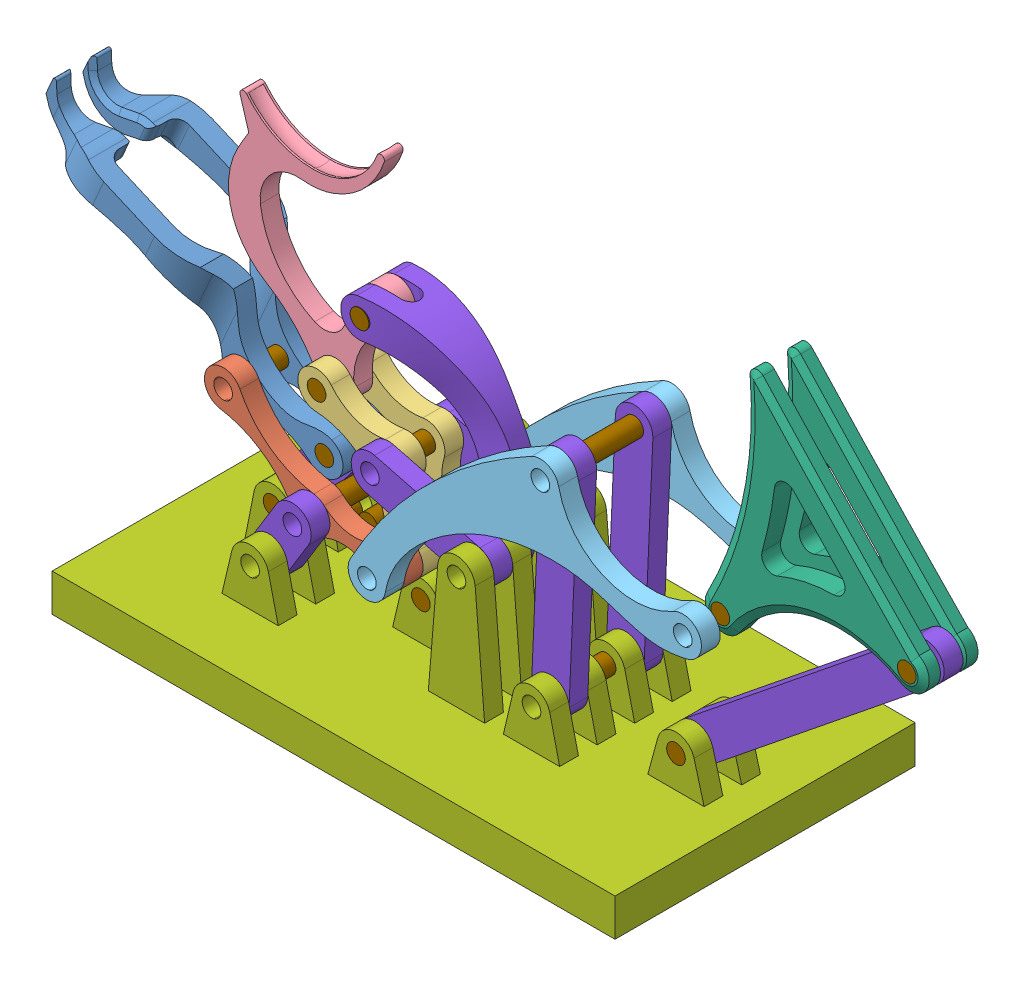
SolidWorks assembly 6-bar, configuration 預設. Lengths in mm.
Overall size (249.01 142.83 80).
39 component instances, 9 part files, 71 mates.
Components (placement in the parent):
- shape_Ar-1: shape_Ar [預設] at (-17.1139 67.4078 9.7386) x (0.35232 -0.935879 0) z (0 0 1) size (78.02 58.45 14.17)
- shape_B-1: shape_B [預設] at (-9.539 47.2864 -8.7614) x (0.80878 -0.588111 0) z (0 0 1) size (56.5 19.67 5)
- shape_Ar-2: shape_Ar [Left預設] at (-17.1139 67.4078 -7.2614) x (0.35232 -0.935879 0) z (0 0 1) size (78.02 58.45 14.17)
- shape_C-1: shape_C [預設] at (33.7626 27.7614 -3.7614) x (-0.208933 0.97793 0) z (0 0 1) size (41 27.3 5)
- shape_C-2: shape_C [預設] at (33.7626 27.7614 6.2386) x (-0.208933 0.97793 0) z (0 0 1) size (41 27.3 5)
- shape_D-1: shape_D [預設] at (10.3686 54.4629 1.2386) x (0.457531 0.889194 0) z (0 0 1) size (62.22 52.19 5)
- shape_E-1: shape_E [預設] at (33.7626 27.7614 16.2386) x (0.945867 0.324554 0) z (0 0 1) size (99 38.21 5)
- shape_E-2: shape_E [預設] at (33.7626 27.7614 -13.7614) x (0.945867 0.324554 0) z (0 0 1) size (99 38.21 5)
- shape_F-1: shape_F [預設] at (117.9447 56.6467 6.2386) x (0.974525 0.224281 0) z (0 0 1) size (61 61.83 5)
- shape_F-2: shape_F [預設] at (117.9447 56.6467 -3.7614) x (0.974525 0.224281 0) z (0 0 1) size (61 61.83 5)
- base-1: base [預設] at (14.1449 20 1.2386) size (150 45 80)
- shape_B-2: shape_B [預設] at (-9.539 47.2864 11.2386) x (0.80878 -0.588111 0) z (0 0 1) size (56.5 19.67 5)
- shaft-1: shaft [預設] at (-1.3551 22 1.2386) x (0.801028 -0.598627 0) z (0 0 1) size (43.4 69.85 15)
- shaft-2: shaft [B] at (7.6449 20 -13.7614) x (0.8526 -0.522565 0) z (0 0 1) size (43.4 69.85 15)
- shaft-3: shaft [B] at (7.6449 20 16.2386) x (0.8526 -0.522565 0) z (0 0 1) size (43.4 69.85 15)
- shaft-4: shaft [E] at (57.6449 40 11.2386) x (0.252413 0.96762 0) z (0 0 1) size (43.4 69.85 15)
- shaft-5: shaft [C] at (24.1449 30.5 -23.7614) x (-0.273862 -0.961769 0) z (0 0 1) size (43.4 69.85 15)
- shaft-6: shaft [D] at (38.1449 20 1.2386) x (0.960894 0.276916 0) z (0 0 1) size (44.01 69.85 15.56)
- shaft-8: shaft [F] at (77.6449 20 11.2386) x (0.999032 -0.043983 0) z (0 0 1) size (43.4 69.85 15)
- shaft-9: shaft [F] at (77.6449 20 -8.7614) x (0.999032 -0.043983 0) z (0 0 1) size (43.4 69.85 15)
- shaft-10: shaft [G] at (106.1449 18.5 1.2386) x (0.627658 -0.778489 0) z (0 0 1) size (43.4 89.43 15)
- shaft-11: shaft [E] at (57.6449 40 -8.7614) x (0.252413 0.96762 0) z (0 0 1) size (43.4 69.85 15)
- axis-1: axis [預設] at (7.6449 20 -3.7614) size (5 5 15)
- axis-2: axis [預設] at (13.9156 30.2312 -6.2614) size (5 5 15)
- axis-3: axis [預設] at (-1.3551 22 -6.2614) size (5 5 15)
- axis-4: axis [預設] at (12.4133 40.4236 -6.2614) size (5 5 15)
- axis-5: axis [預設] at (-9.539 47.2864 -6.2614) size (5 5 15)
- axis-6: axis [預設] at (33.7626 27.7614 -6.2614) size (5 5 15)
- axis-7: axis [預設] at (38.1449 20 -6.2614) size (5 5 15)
- axis-8: axis [預設] at (57.6449 40 -6.2614) size (5 5 15)
- axis-9: axis [預設] at (24.1449 30.5 -6.2614) size (5 5 15)
- axis-10: axis [預設] at (29.5839 47.32 -6.2614) size (5 5 15)
- axis-11: axis [預設] at (10.3686 54.4629 -6.2614) size (5 5 15)
- axis-12: axis [預設] at (21.8068 76.6928 -6.2614) size (5 5 15)
- axis-13: axis [預設] at (79.998 73.4482 -6.2614) size (5 5 15)
- axis-14: axis [預設] at (77.6449 20 -6.2614) size (5 5 15)
- axis-15: axis [預設] at (117.9447 56.6467 -6.2614) size (5 5 15)
- axis-16: axis [預設] at (106.1449 18.5 -6.2614) size (5 5 15)
- axis-17: axis [預設] at (167.6455 68.085 -6.2614) size (5 5 15)
Mates (geometry in assembly coordinates):
- 同軸心2: concentric aligned: cylinder of shape_B-2 through (13.9156 30.2312 13.7386) axis (0 0 -1) radius 2.5; cylinder of shaft-2 through (13.9156 30.2312 -11.2614) axis (0 0 -1) radius 2.5
- 同軸心3: concentric aligned: cylinder of shape_B-1 through (13.9156 30.2312 -6.2614) axis (0 0 -1) radius 2.5; cylinder of shaft-2 through (13.9156 30.2312 -11.2614) axis (0 0 -1) radius 2.5
- 重合/共線/共點16: coincident anti-aligned: plane of shape_B-1 through (33.7626 27.7614 -11.2614) normal (0 0 -1); plane of shaft-2 through (7.6449 20 -11.2614) normal (0 0 1)
- 重合/共線/共點17: coincident anti-aligned: plane of shape_B-2 through (33.7626 27.7614 13.7386) normal (0 0 1); plane of shaft-3 through (7.6449 20 13.7386) normal (0 0 -1)
- 同軸心6: concentric aligned: cylinder of shape_B-2 through (13.9156 30.2312 13.7386) axis (0 0 -1) radius 2.5; cylinder of shaft-3 through (13.9156 30.2312 18.7386) axis (0 0 -1) radius 2.5
- 重合/共線/共點19: coincident aligned: circle of shape_C-2; circle of shape_B-2
- 重合/共線/共點22: coincident aligned: circle of shape_B-1; circle of shape_C-1
- 重合/共線/共點23: coincident aligned: circle of shape_C-2; circle of shape_D-1
- 重合/共線/共點24: coincident aligned: circle of shape_C-1; circle of shape_D-1
- 同軸心15: concentric aligned: cylinder of shape_B-1 through (33.7626 27.7614 -6.2614) axis (0 0 -1) radius 2.5; cylinder of shaft-5 through (33.7626 27.7614 -21.2614) axis (0 0 -1) radius 2.5
- 重合/共線/共點26: coincident anti-aligned: circle of shape_D-1; circle of shaft-6
- 重合/共線/共點28: coincident aligned: circle of shape_B-1; circle of shape_E-2
- 重合/共線/共點29: coincident aligned: circle of shape_E-1; circle of shape_B-2
- 重合/共線/共點30: coincident aligned: circle of shape_E-1; circle of shaft-8
- 重合/共線/共點31: coincident aligned: circle of shape_E-2; circle of shaft-9
- 同軸心21: concentric aligned: cylinder of shape_E-1 through (117.9447 56.6467 18.7386) axis (0 0 -1) radius 2.5; cylinder of shape_F-1 through (117.9447 56.6467 8.7386) axis (0 0 -1) radius 2.5
- 同軸心22: concentric aligned: cylinder of shape_E-2 through (117.9447 56.6467 -11.2614) axis (0 0 -1) radius 2.5; cylinder of shape_F-2 through (117.9447 56.6467 -1.2614) axis (0 0 -1) radius 2.5
- 重合/共線/共點32: coincident anti-aligned: plane of shape_F-1 through (117.9447 56.6467 8.7386) normal (0 0 1); plane of shaft-8 through (77.6449 20 8.7386) normal (0 0 -1)
- 重合/共線/共點33: coincident anti-aligned: plane of shape_F-2 through (117.9447 56.6467 -6.2614) normal (0 0 -1); plane of shaft-9 through (77.6449 20 -6.2614) normal (0 0 1)
- 重合/共線/共點34: coincident aligned: circle of shape_F-1; circle of shaft-10
- 重合/共線/共點35: coincident aligned: circle of shape_F-2; circle of shaft-10
- 重合/共線/共點37: coincident anti-aligned: circle of base-1; circle of shaft-10
- 同軸心25: concentric aligned: cylinder of base-1 through (77.6449 20 18.7386) axis (0 0 -1) radius 2.5; cylinder of shaft-8 through (77.6449 20 13.7386) axis (0 0 -1) radius 2.5
- 同軸心26: concentric aligned: cylinder of base-1 through (77.6449 20 18.7386) axis (0 0 -1) radius 2.5; cylinder of shaft-9 through (77.6449 20 -6.2614) axis (0 0 -1) radius 2.5
- 同軸心27: concentric aligned: cylinder of base-1 through (57.6449 40 18.7386) axis (0 0 -1) radius 2.5; cylinder of shaft-4 through (57.6449 40 13.7386) axis (0 0 -1) radius 2.5
- 同軸心28: concentric anti-aligned: cylinder of base-1 through (38.1449 20 8.7386) axis (0 0 -1) radius 2.5; cylinder of shaft-6 through (38.1449 20 -23.7614) axis (0 0 1) radius 2.5
- 同軸心29: concentric aligned: cylinder of base-1 through (7.6449 20 23.7386) axis (0 0 -1) radius 2.5; cylinder of shaft-3 through (7.6449 20 18.7386) axis (0 0 -1) radius 2.5
- 同軸心30: concentric aligned: cylinder of base-1 through (-1.3551 22 8.7386) axis (0 0 -1) radius 2.5; cylinder of shaft-1 through (-1.3551 22 3.7386) axis (0 0 -1) radius 2.5
- 重合/共線/共點41: coincident anti-aligned: circle of base-1; circle of shaft-5
- 同軸心31: concentric aligned: cylinder of base-1 through (7.6449 20 23.7386) axis (0 0 -1) radius 2.5; cylinder of shaft-2 through (7.6449 20 -11.2614) axis (0 0 -1) radius 2.5
- 重合/共線/共點43: coincident anti-aligned: plane of base-1 through (47.7822 45 13.7386) normal (0 0 -1); plane of shaft-4 through (57.6449 40 13.7386) normal (0 0 1)
- 重合/共線/共點44: coincident aligned: circle of shape_C-1; circle of shaft-11
- 重合/共線/共點45: coincident aligned: circle of base-1; circle of shaft-11
- 同軸心32: concentric aligned: cylinder of shape_C-1 through (29.5839 47.32 -1.2614) axis (0 0 -1) radius 2.5; cylinder of shaft-4 through (29.5839 47.32 13.7386) axis (0 0 -1) radius 2.5
- 同軸心33: concentric aligned: cylinder of shape_F-2 through (167.6455 68.085 -1.2614) axis (0 0 -1) radius 2.5; cylinder of axis-17 through (167.6455 68.085 8.7386) axis (0 0 -1) radius 2.5
- 同軸心34: concentric aligned: cylinder of base-1 through (106.1449 18.5 8.7386) axis (0 0 -1) radius 2.5; cylinder of axis-16 through (106.1449 18.5 8.7386) axis (0 0 -1) radius 2.5
- 同軸心35: concentric aligned: cylinder of shape_E-2 through (117.9447 56.6467 -11.2614) axis (0 0 -1) radius 2.5; cylinder of axis-15 through (117.9447 56.6467 8.7386) axis (0 0 -1) radius 2.5
- 同軸心36: concentric aligned: cylinder of base-1 through (77.6449 20 18.7386) axis (0 0 -1) radius 2.5; cylinder of axis-14 through (77.6449 20 8.7386) axis (0 0 -1) radius 2.5
- 同軸心37: concentric aligned: cylinder of shape_E-2 through (79.998 73.4482 -11.2614) axis (0 0 -1) radius 2.5; cylinder of axis-13 through (79.998 73.4482 8.7386) axis (0 0 -1) radius 2.5
- 同軸心38: concentric anti-aligned: cylinder of shaft-6 through (21.8068 76.6928 -23.7614) axis (0 0 1) radius 2.5; cylinder of axis-12 through (21.8068 76.6928 8.7386) axis (0 0 -1) radius 2.5
- 同軸心39: concentric aligned: cylinder of shape_C-1 through (10.3686 54.4629 -1.2614) axis (0 0 -1) radius 2.5; cylinder of axis-11 through (10.3686 54.4629 8.7386) axis (0 0 -1) radius 2.5
- 同軸心40: concentric aligned: cylinder of shaft-11 through (29.5839 47.32 -6.2614) axis (0 0 -1) radius 2.5; cylinder of axis-10 through (29.5839 47.32 8.7386) axis (0 0 -1) radius 2.5
- 同軸心41: concentric anti-aligned: cylinder of base-1 through (24.1449 30.5 -31.2614) axis (0 0 1) radius 2.5; cylinder of axis-9 through (24.1449 30.5 8.7386) axis (0 0 -1) radius 2.5
- 重合/共線/共點46: coincident aligned: plane of axis-16 through (106.1449 18.5 8.7386) normal (0 0 1); plane of axis-17 through (167.6455 68.085 8.7386) normal (0 0 1)
- 重合/共線/共點47: coincident aligned: plane of axis-15 through (117.9447 56.6467 8.7386) normal (0 0 1); plane of axis-16 through (106.1449 18.5 8.7386) normal (0 0 1)
- 重合/共線/共點48: coincident aligned: plane of axis-14 through (77.6449 20 8.7386) normal (0 0 1); plane of axis-15 through (117.9447 56.6467 8.7386) normal (0 0 1)
- 重合/共線/共點49: coincident aligned: plane of axis-13 through (79.998 73.4482 8.7386) normal (0 0 1); plane of axis-14 through (77.6449 20 8.7386) normal (0 0 1)
- 重合/共線/共點50: coincident aligned: plane of axis-12 through (21.8068 76.6928 8.7386) normal (0 0 1); plane of axis-13 through (79.998 73.4482 8.7386) normal (0 0 1)
- 重合/共線/共點51: coincident aligned: plane of axis-11 through (10.3686 54.4629 8.7386) normal (0 0 1); plane of axis-12 through (21.8068 76.6928 8.7386) normal (0 0 1)
- 重合/共線/共點52: coincident aligned: plane of axis-9 through (24.1449 30.5 8.7386) normal (0 0 1); plane of axis-10 through (29.5839 47.32 8.7386) normal (0 0 1)
- 重合/共線/共點53: coincident aligned: plane of axis-9 through (24.1449 30.5 8.7386) normal (0 0 1); plane of axis-11 through (10.3686 54.4629 8.7386) normal (0 0 1)
- 重合/共線/共點54: coincident aligned: plane of shape_F-1 through (117.9447 56.6467 8.7386) normal (0 0 1); plane of axis-17 through (167.6455 68.085 8.7386) normal (0 0 1)
- 同軸心43: concentric aligned: cylinder of base-1 through (57.6449 40 18.7386) axis (0 0 -1) radius 2.5; cylinder of axis-8 through (57.6449 40 8.7386) axis (0 0 -1) radius 2.5
- 同軸心44: concentric aligned: cylinder of base-1 through (38.1449 20 8.7386) axis (0 0 -1) radius 2.5; cylinder of axis-7 through (38.1449 20 8.7386) axis (0 0 -1) radius 2.5
- 同軸心45: concentric aligned: cylinder of shaft-5 through (33.7626 27.7614 -21.2614) axis (0 0 -1) radius 2.5; cylinder of axis-6 through (33.7626 27.7614 8.7386) axis (0 0 -1) radius 2.5
- 同軸心46: concentric aligned: cylinder of shape_B-1 through (-9.539 47.2864 -6.2614) axis (0 0 -1) radius 2.5; cylinder of axis-5 through (-9.539 47.2864 8.7386) axis (0 0 -1) radius 2.5
- 同軸心48: concentric aligned: cylinder of base-1 through (-1.3551 22 8.7386) axis (0 0 -1) radius 2.5; cylinder of axis-3 through (-1.3551 22 8.7386) axis (0 0 -1) radius 2.5
- 同軸心49: concentric aligned: cylinder of shaft-2 through (13.9156 30.2312 -11.2614) axis (0 0 -1) radius 2.5; cylinder of axis-2 through (13.9156 30.2312 8.7386) axis (0 0 -1) radius 2.5
- 同軸心50: concentric aligned: cylinder of base-1 through (7.6449 20 23.7386) axis (0 0 -1) radius 2.5; cylinder of axis-1 through (7.6449 20 11.2386) axis (0 0 -1) radius 2.5
- 重合/共線/共點55: coincident aligned: plane of axis-7 through (38.1449 20 8.7386) normal (0 0 1); plane of axis-8 through (57.6449 40 8.7386) normal (0 0 1)
- 重合/共線/共點56: coincident aligned: plane of axis-6 through (33.7626 27.7614 8.7386) normal (0 0 1); plane of axis-7 through (38.1449 20 8.7386) normal (0 0 1)
- 重合/共線/共點57: coincident aligned: plane of axis-4 through (12.4133 40.4236 8.7386) normal (0 0 1); plane of axis-5 through (-9.539 47.2864 8.7386) normal (0 0 1)
- 重合/共線/共點58: coincident aligned: plane of axis-4 through (12.4133 40.4236 8.7386) normal (0 0 1); plane of axis-6 through (33.7626 27.7614 8.7386) normal (0 0 1)
- 重合/共線/共點59: coincident aligned: plane of axis-3 through (-1.3551 22 8.7386) normal (0 0 1); plane of axis-5 through (-9.539 47.2864 8.7386) normal (0 0 1)
- 重合/共線/共點60: coincident aligned: plane of axis-2 through (13.9156 30.2312 -6.2614) normal (0 0 -1); plane of axis-5 through (-9.539 47.2864 -6.2614) normal (0 0 -1)
- 重合/共線/共點61: coincident aligned: plane of axis-8 through (57.6449 40 8.7386) normal (0 0 1); plane of axis-17 through (167.6455 68.085 8.7386) normal (0 0 1)
- 重合/共線/共點62: coincident anti-aligned: circle of shape_B-1; circle of shape_Ar-2
- 同軸心51: concentric anti-aligned: cylinder of shape_Ar-2 through (12.4133 40.4236 -13.2614) axis (0 0 1) radius 2.5; cylinder of axis-4 through (12.4133 40.4236 8.7386) axis (0 0 -1) radius 2.5
- 同軸心52: concentric aligned: cylinder of shaft-1 through (12.4133 40.4236 3.7386) axis (0 0 -1) radius 2.5; cylinder of axis-4 through (12.4133 40.4236 8.7386) axis (0 0 -1) radius 2.5
- 同軸心53: concentric aligned: cylinder of shape_Ar-1 through (12.4133 40.4236 15.7386) axis (0 0 -1) radius 2.5; cylinder of axis-4 through (12.4133 40.4236 8.7386) axis (0 0 -1) radius 2.5
- 同軸心54: concentric aligned: cylinder of shape_Ar-1 through (-9.539 47.2864 15.7386) axis (0 0 -1) radius 2.5; cylinder of axis-5 through (-9.539 47.2864 8.7386) axis (0 0 -1) radius 2.5
